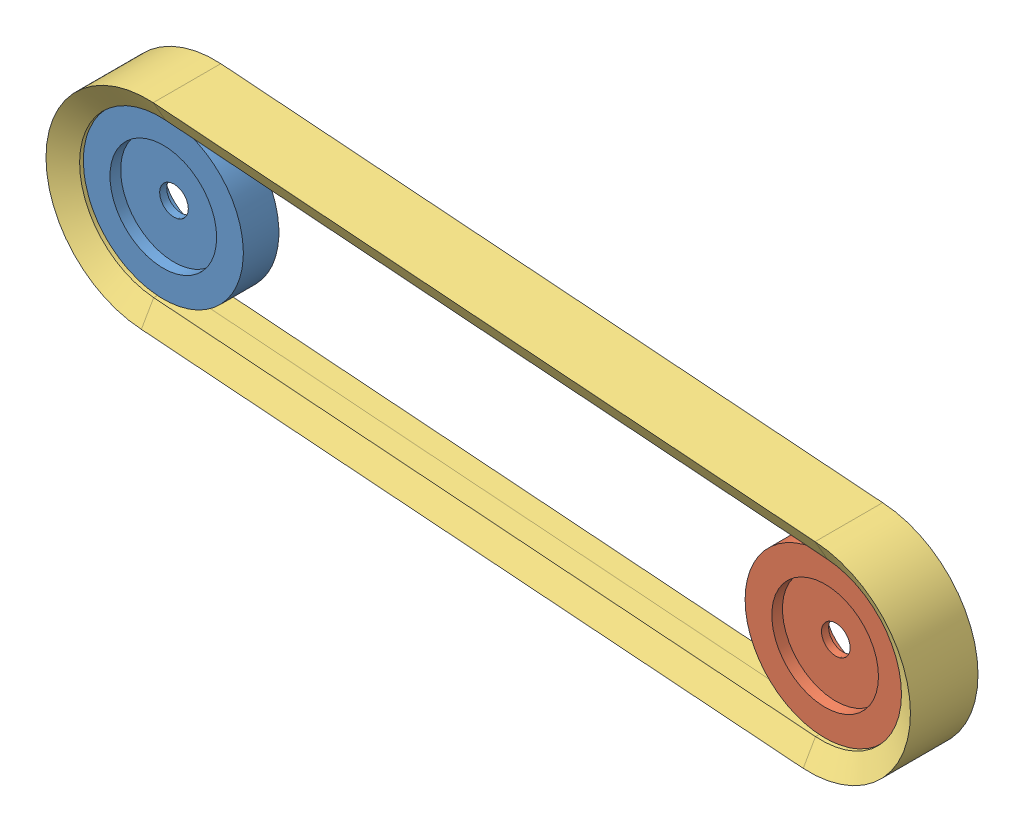
SolidWorks assembly Assem1, configuration Default. Lengths in mm.
Overall size (245.21 72.4 19).
4 component instances, 3 part files, 0 mates.
Components (placement in the parent):
- conveyer belt-1: conveyer belt [Default] at (-5.4853 124.2271 185.8146) size (245.21 72.4 19)
  - wheel-1: wheel [Default] at (13.891 13.857 -10) size (49.8 45 10)
  - wheel2-1: wheel2 [Default] at (200 0 -10) size (49.8 45 10)
  - Belt1-3^conveyer belt-1: Belt1-3^conveyer belt [Default] at (13.891 13.857 -5) x (-1 0 0) z (0 0 -1) size (245.21 72.4 19) (virtual)
